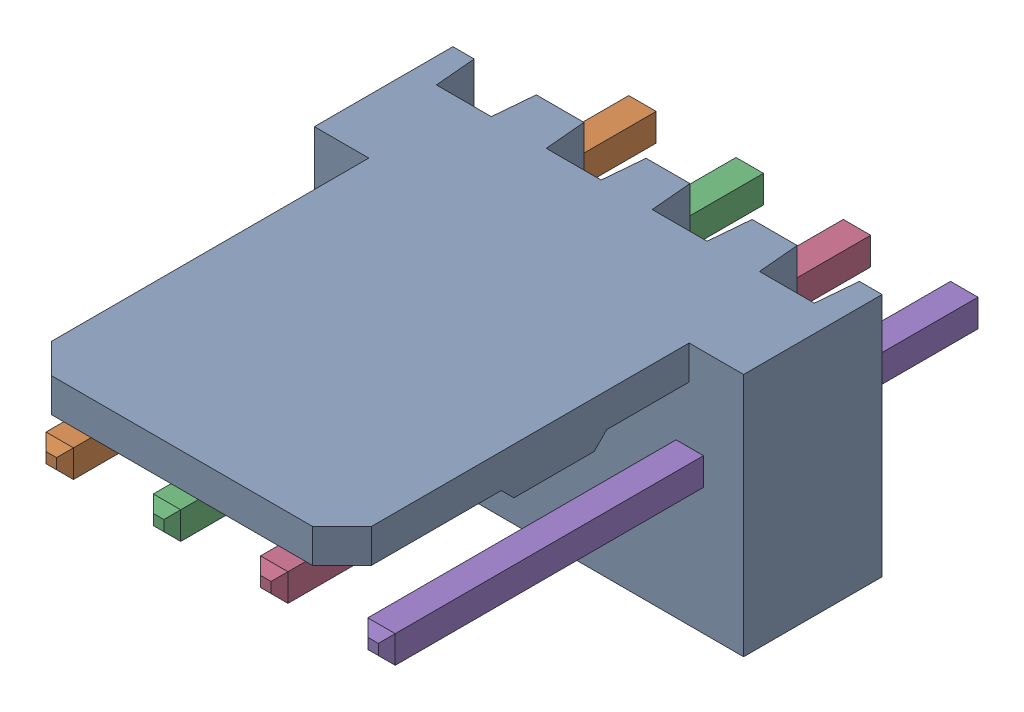
SolidWorks assembly Molex PCB 4 pin v3_2, configuration Predeterminado. Lengths in mm.
Overall size (10.16 5.79 14.92).
5 component instances, 2 part files, 0 mates.
Components (placement in the parent):
- BASE9710016-1: BASE9710016 [Predeterminado] at (2.54 2.895 -8.22) size (10.16 5.79 11.5)
- PINO9710016-1: PINO9710016 [Predeterminado] at (1.27 3.325 -0.72) size (0.65 0.65 14.2)
- PINO9710016-2: PINO9710016 [Predeterminado] at (3.81 3.325 -0.72) size (0.65 0.65 14.2)
- PINO9710016-3: PINO9710016 [Predeterminado] at (6.35 3.325 -0.72) size (0.65 0.65 14.2)
- PINO9710016-4: PINO9710016 [Predeterminado] at (8.89 3.325 -0.72) size (0.65 0.65 14.2)
